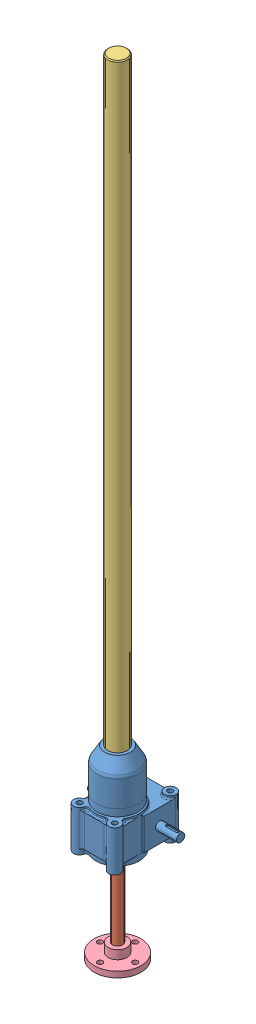
SolidWorks assembly EM1_BSJ_I_20_1_SSE_1_SSE_2_FP_1000_S, configuration Valor predeterminado. Lengths in mm.
Overall size (152.46 1342.73 119.88).
4 component instances, 4 part files, 5 mates.
Components (placement in the parent):
- housing_I-SSE-SSE-1: housing_I-SSE-SSE [Valor predeterminado] at origin size (152.46 163.5 119.88)
- UILiftShaft_1-BSJ-I-1: UILiftShaft_1-BSJ-I [Valor predeterminado] at (0 1039.256 0) x (0.809981 0 -0.586456) z (0 1 0) size (20.5 20.5 1203.1)
- UIStemCover_1-BSJ-I-1: UIStemCover_1-BSJ-I [Valor predeterminado] at (0 153.3825 0) x (1 0 0) z (0 1 0) size (33.5 33.5 1025.5)
- Top-Plate_1-BSJ-I-1: Top-Plate_1-BSJ-I [Valor predeterminado] at (0 -153.8442 0) x (0 1 0) z (-1 0 0) size (25 80 80)
Mates (geometry in assembly coordinates):
- Concêntrico1: concentric aligned: cylinder of housing_I-SSE-SSE-1 through (0 153.3825 0) axis (0 -1 0) radius 10.25; cylinder of UILiftShaft_1-BSJ-I-1 through (0 1039.256 0) axis (0 -1 0) radius 8.75
- Concêntrico2: concentric aligned: cylinder of UILiftShaft_1-BSJ-I-1 through (0 1039.256 0) axis (0 -1 0) radius 8.75; cylinder of Top-Plate_1-BSJ-I-1 through (0 -170.8037 0) axis (0 -1 0) radius 16
- Coincidente2: coincident anti-aligned: plane of UILiftShaft_1-BSJ-I-1 through (-5.1315 -138.8442 -7.0873) normal (0 -1 0); plane of Top-Plate_1-BSJ-I-1 through (0 -138.8442 -16) normal (0 1 0)
- Concêntrico3: concentric anti-aligned: cylinder of UILiftShaft_1-BSJ-I-1 through (0 1039.256 0) axis (0 -1 0) radius 8.75; cylinder of UIStemCover_1-BSJ-I-1 through (0 153.3825 0) axis (0 1 0) radius 16.75
- Coincidente3: coincident anti-aligned: plane of housing_I-SSE-SSE-1 through (0 153.3825 21.8588) normal (0 1 0); circle of UIStemCover_1-BSJ-I-1
